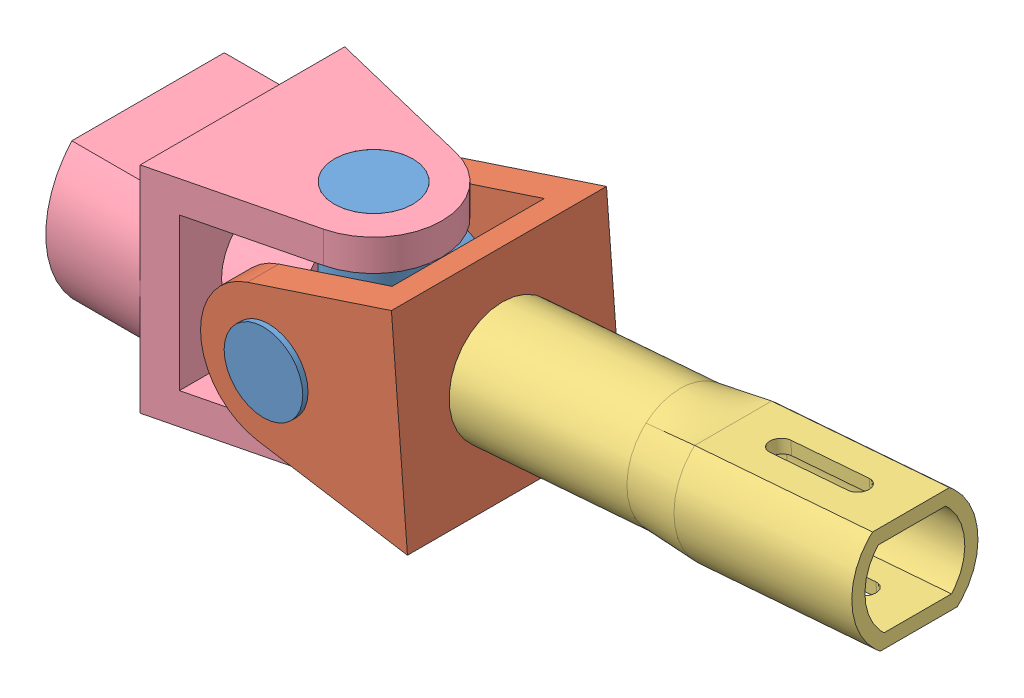
SolidWorks assembly JuntaUniversalSup, configuration Default. Lengths in mm.
Overall size (146.54 42.4 42).
4 component instances, 4 part files, 7 mates.
Components (placement in the parent):
- Rotula-1: Rotula [Default] at (17.1985 21.9918 -38.8946) x (-1 0 0) z (0 0 -1) size (15 42 42)
- RotulaUniversalB-1: RotulaUniversalB [Default] at (32.1526 23.1648 -39.3946) x (-0.996937 -0.078203 0) z (-0.078203 0.996937 0) size (38 41 39)
- VeioRotulaSup-1: VeioRotulaSup [Default] at (6.2322 21.1315 -39.3946) x (0.996937 0.078203 0) z (0 0 1) size (86 22.01 24.1)
- RotulaUniversalA-1: RotulaUniversalA [Default] at (2.1985 22.4918 -38.8946) size (56 41 39)
Mates (geometry in assembly coordinates):
- Concentric1: concentric anti-aligned: cylinder of Rotula-1 through (17.1985 42.9918 -38.8946) axis (0 1 0) radius 7.5; cylinder of RotulaUniversalA-1 through (17.1985 1.9918 -38.8946) axis (0 -1 0) radius 7.5
- Coincident1: coincident aligned: plane of Rotula-1 through (24.6985 42.9918 -38.8946) normal (0 1 0); plane of RotulaUniversalA-1 through (-7.8015 42.9918 -19.3946) normal (0 1 0)
- Concentric2: concentric anti-aligned: cylinder of Rotula-1 through (17.1985 21.9918 -17.8946) axis (0 0 1) radius 7.5; cylinder of RotulaUniversalB-1 through (17.1985 21.9918 -59.8946) axis (0 0 -1) radius 7.5
- Coincident2: coincident aligned: plane of Rotula-1 through (24.6985 21.9918 -59.8946) normal (0 0 -1); plane of RotulaUniversalB-1 through (40.597 43.3871 -59.8946) normal (0 0 -1)
- Concentric3: concentric aligned: cylinder of RotulaUniversalB-1 through (4.2383 20.9751 -39.3946) axis (0.996937 0.078203 0) radius 10; cylinder of VeioRotulaSup-1 through (114.1309 29.5954 -39.3946) axis (0.996937 0.078203 0) radius 10
- Coincident8: coincident anti-aligned: plane of RotulaUniversalB-1 through (40.597 43.3871 -26.3946) normal (0.996937 0.078203 0); plane of VeioRotulaSup-1 through (41.3399 33.9162 -39.3946) normal (-0.996937 -0.078203 0)
- Parallel2: parallel: line of RotulaUniversalB-1 through (40.597 43.3871 -18.8946) axis (0 0 -1); plane of VeioRotulaSup-1 through (54.7276 34.4648 -46.726) normal (-0.078203 0.996937 0)
